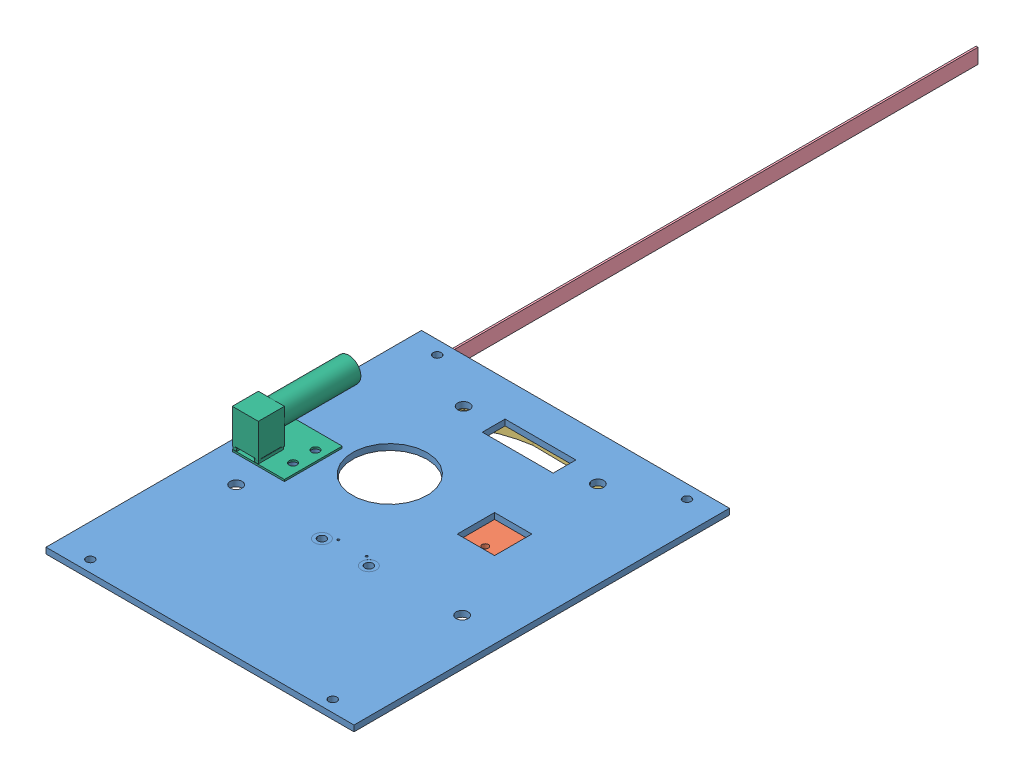
SolidWorks assembly B3_-X_panel, configuration ﾃﾞﾌｫﾙﾄ. Lengths in mm.
Overall size (82.6 17.1 243.2).
7 component instances, 6 part files, 10 mates.
Components (placement in the parent):
- B3_-X_panel-1: B3_-X_panel [Default] at (-23.2463 -4.453 97.5) size (82.6 1.6 100.7)
- B3_GPS_patch antenna-1: B3_GPS_patch antenna [Default] at (21.482 -8.453 106.9818) size (25 4 25)
- Antenna_before-1: Antenna_before [Default] at (-2.2383 -4.953 71.3601) x (-1 0 0) z (0 -1 0) size (69.77 70.87 4)
- B3_antenna_parts-1: B3_antenna_parts [Default] at (-2.9483 10.172 18.667) x (-0.269009 0.151983 -0.951071) z (-0.889289 -0.418402 0.184673) size (190.05 64.9 41.64)
  - Monopole Antenna_17 - コピー-1: Monopole Antenna_17 - コピー [ﾃﾞﾌｫﾙﾄ] at (96.5445 25.6028 16.4245) x (-0.951071 -0.247711 0.184673) z (0.269009 -0.369863 0.889289) size (196 4 0.5)
  - B2_antenna fixing parts2-1: B2_antenna fixing parts2 [ﾃﾞﾌｫﾙﾄ] at (-84.5441 -19.7206 46.4497) x (0.951071 0.247711 -0.184673) z (0.269009 -0.369863 0.889289) size (14 5 10.5)
  - B3_antenna connector-1: B3_antenna connector [ﾃﾞﾌｫﾙﾄ] at (-86.1125 -28.2252 45.917) x (-0.151983 0.895455 0.418402) z (0.951071 0.247711 -0.184673) size (17.1 14 27.53)
Mates (geometry in assembly coordinates):
- Coincident272: coincident anti-aligned: plane of B3_-X_panel-1 through (-23.2463 -2.853 97.5) normal (0 1 0); plane of ? through (1.4937 -2.853 132.7375) normal (0 -1 0)
- Coincident273: coincident anti-aligned: plane of B3_-X_panel-1 through (-23.2463 -4.453 97.5) normal (0 -1 0); plane of B3_GPS_patch antenna-1 through (21.482 -4.453 106.9818) normal (0 1 0)
- 距離3: distance = 18.8 mm aligned: plane of ? through (-22.0063 -1.553 148.7375) normal (-1 0 0); plane of B3_-X_panel-1 through (-40.8063 -2.853 166.7375) normal (-1 0 0)
- 距離4: distance = 18 mm aligned: plane of ? through (24.9937 -1.553 148.7375) normal (0 0 1); plane of B3_-X_panel-1 through (-23.2463 -4.453 166.7375) normal (0 0 1)
- ﾛｯｸ1: lock: unknown of ?
- 距離6: distance = 38 mm anti-aligned: plane of B3_-X_panel-1 through (41.7937 -2.853 66.0375) normal (1 0 0); plane of B3_GPS_patch antenna-1 through (3.7937 -4.453 91.0375) normal (-1 0 0)
- 距離7: distance = 25 mm aligned: plane of B3_GPS_patch antenna-1 through (3.7937 -4.453 91.0375) normal (0 0 -1); plane of B3_-X_panel-1 through (-23.2463 -4.453 66.0375) normal (0 0 -1)
- 一致68: coincident anti-aligned: plane of B3_-X_panel-1 through (-23.2463 -4.453 97.5) normal (0 -1 0); plane of B3_antenna_parts-1/B2_antenna fixing parts2-1 through (-28.8063 -4.453 112.5375) normal (0 1 0)
- 同心円1: concentric anti-aligned: cylinder of B3_-X_panel-1 through (-26.7563 -12.853 108.5375) axis (0 1 0) radius 1.1; cylinder of B3_antenna_parts-1/B2_antenna fixing parts2-1 through (-26.7563 -9.453 108.5375) axis (0 -1 0) radius 1.1
- 同心円2: concentric anti-aligned: cylinder of B3_-X_panel-1 through (-26.7563 -12.853 114.5375) axis (0 1 0) radius 1.1; cylinder of B3_antenna_parts-1/B2_antenna fixing parts2-1 through (-26.7563 -9.453 114.5375) axis (0 -1 0) radius 1.1
